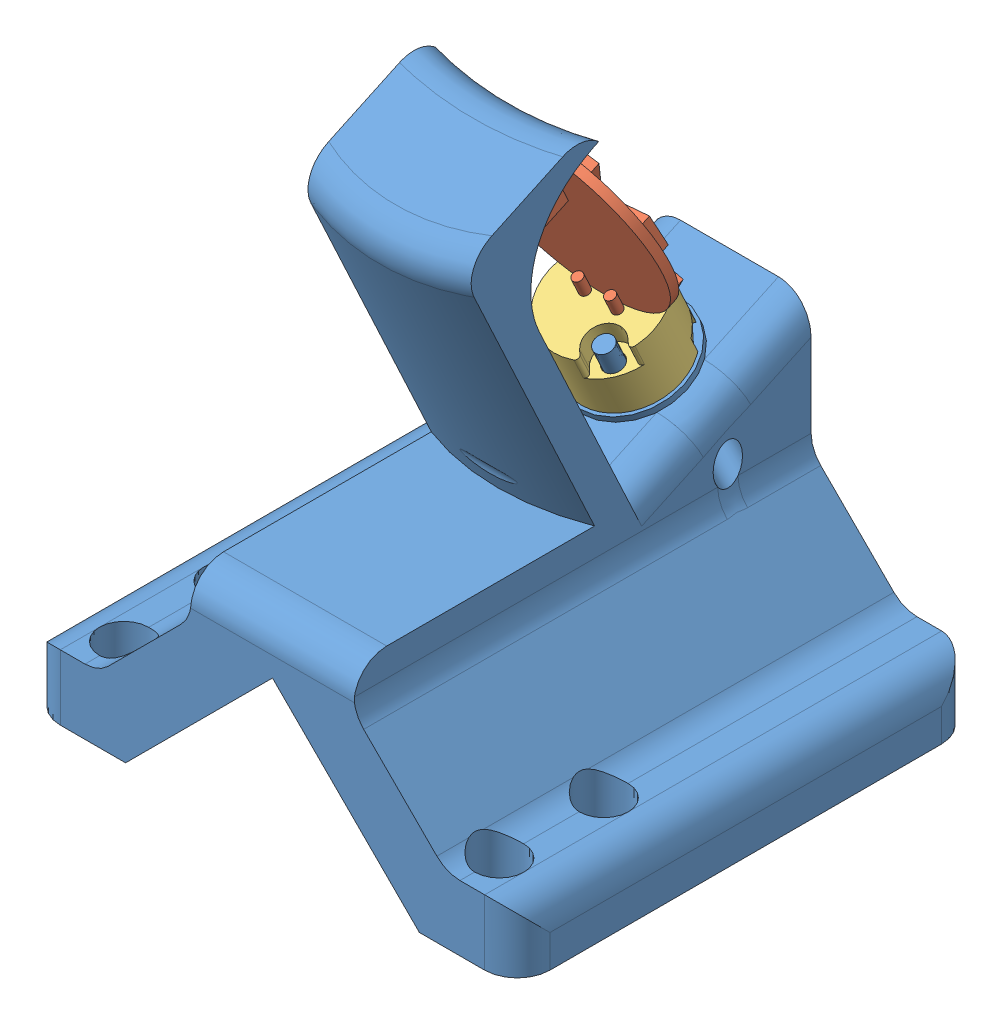
SolidWorks assembly Ecklampe, configuration Standard. Lengths in mm.
Overall size (75 82.7 74.76).
3 component instances, 3 part files, 6 mates.
Components (placement in the parent):
- Ecke-1: Ecke [Standard] at (0.8049 -12.0874 100) size (75 82.7 70)
- G4 LED-1: G4 LED [Standard] at (0.8049 26.7881 125.3083) x (1 0 0) z (0 0.906308 0.422618) size (30 9.9 34.79)
- G4 Sockel-1: G4 Sockel [Standard] at (0.8049 3.8135 115.4226) x (0.707107 -0.298836 0.640856) z (0 0.906308 0.422618) size (16 16 33.5)
Mates (geometry in assembly coordinates):
- Deckungsgleich1: coincident anti-aligned: plane of Ecke-1 through (0.8049 3.8135 115.4226) normal (0 0.906308 0.422618); plane of G4 Sockel-1 through (0.8049 3.8135 115.4226) normal (0 -0.906308 -0.422618)
- Konzentrisch1: concentric anti-aligned: cylinder of Ecke-1 through (-3.4377 14.6696 115.8037) axis (0 -0.906308 -0.422618) radius 1.4; cylinder of G4 Sockel-1 through (-3.4377 5.6065 111.5775) axis (0 0.906308 0.422618) radius 1.5
- Konzentrisch2: concentric anti-aligned: cylinder of Ecke-1 through (5.0476 11.0835 123.4939) axis (0 -0.906308 -0.422618) radius 1.4; cylinder of G4 Sockel-1 through (5.0476 2.0205 119.2678) axis (0 0.906308 0.422618) radius 1.5
- Deckungsgleich2: coincident anti-aligned: cylinder of G4 LED-1 through (-1.6951 15.3371 120.7962) axis (0 -0.906308 -0.422618) radius 0.75; circle of G4 Sockel-1
- Konzentrisch3: concentric anti-aligned: cylinder of G4 LED-1 through (3.3049 15.3371 120.7962) axis (0 -0.906308 -0.422618) radius 0.75; cylinder of G4 Sockel-1 through (3.3049 3.8135 115.4226) axis (0 0.906308 0.422618) radius 0.75
- Tangential1: tangent anti-aligned: cylinder of G4 LED-1 through (0.8049 27.3798 124.0395) axis (0 -0.422618 0.906308) radius 15; plane of G4 Sockel-1 through (0.8049 12.8766 119.6488) normal (0 0.906308 0.422618)
